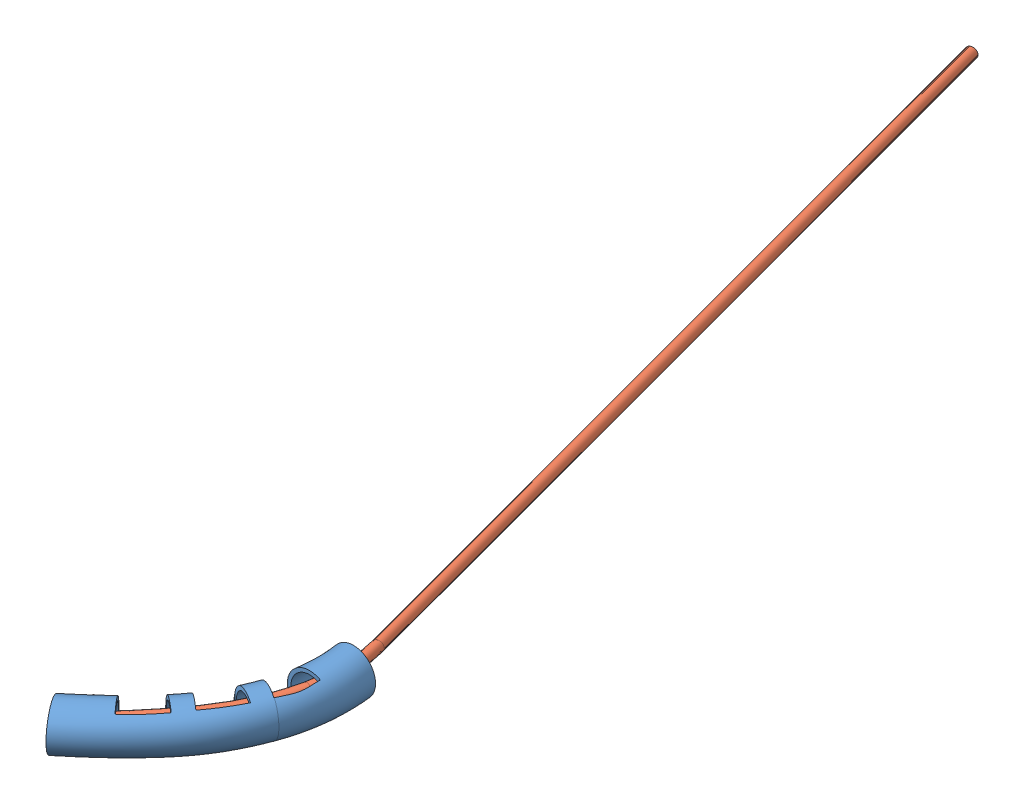
SolidWorks assembly cable + square joint_curve 2 assem, configuration Default. Lengths in mm.
Overall size (18.55 1.24 29.8).
2 component instances, 2 part files, 2 mates.
Components (placement in the parent):
- Arushri_Tube_SquareJoint_curve 2-1: Arushri_Tube_SquareJoint_curve 2 [Default] at (3.9357 4.1267 4.0971) size (4.02 1.24 16.37)
- cable_curve2-1: cable_curve2 [Default] at (1.1737 4.1267 8.6296) x (-0.396928 0 -0.91785) z (0 1 0) size (27.85 8.17 0.5)
Mates (geometry in assembly coordinates):
- Concentric1: concentric anti-aligned: circle of Arushri_Tube_SquareJoint_curve 2-1; circle of cable_curve2-1
- Coincident3: coincident aligned: circle of Arushri_Tube_SquareJoint_curve 2-1; circle of cable_curve2-1
